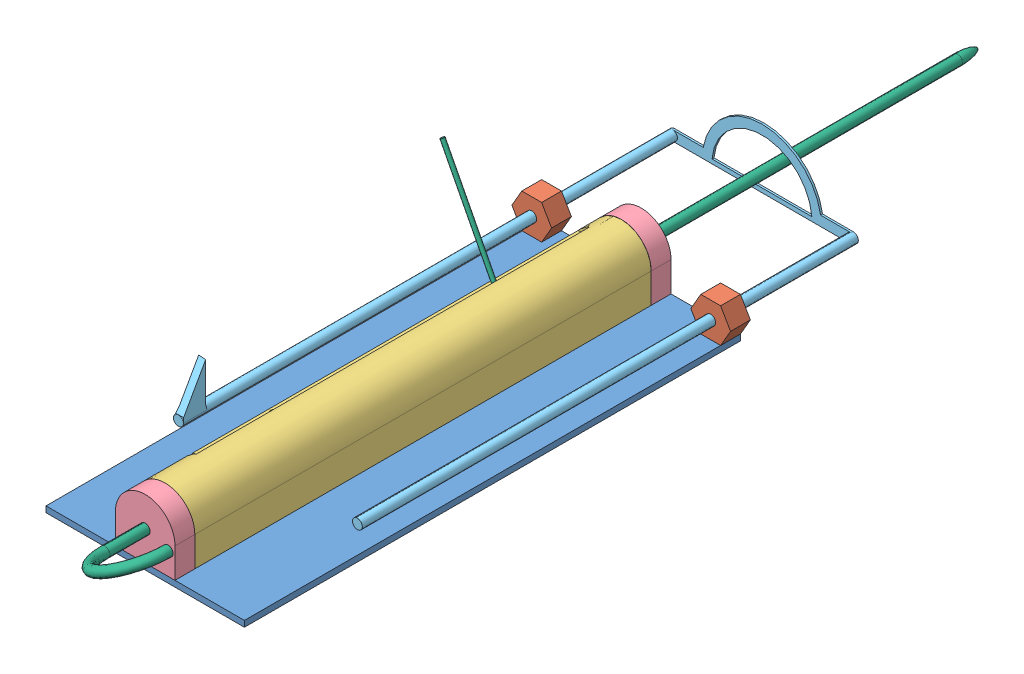
SolidWorks assembly first, configuration Default. Lengths in mm.
Overall size (110.2 109.57 460.1).
10 component instances, 7 part files, 15 mates.
Components (placement in the parent):
- βάση-1: βάση [Default] at (31.2253 106.149 101.923) x (0 0 1) z (-1 0 0) size (250 3 100)
- Βίδα-1: Βίδα [Default] at (31.0441 117.8093 91.4061) x (1 0 0) z (0 -1 0) size (20 10 17.32)
- Βίδα-2: Βίδα [Default] at (121.2441 117.8093 91.4061) x (1 0 0) z (0 -1 0) size (20 10 17.32)
- Σωλήνας-1: Σωλήνας [Default] at (76.5697 124.4973 -23.5939) x (1 0 0) z (0 -1 0) size (30 230 30) (hidden)
- Σωλήνας-2: Σωλήνας [Default] at (76.2441 124.149 331.4061) x (-1 0 0) z (0 -1 0) size (30 230 30)
- καπάκι-1: καπάκι [Default] at (76.2441 124.149 91.4061) x (1 0 0) z (0 -1 0) size (30 10 30)
- σκανδάλη2-1: σκανδάλη2 [Default<As Machined>] at (76.1441 115.3093 29.4831) x (1 0 0) z (0 -1 0) size (95.2 250.14 50)
- άξονας-1: άξονας [Default] at (76.2441 124.149 158.9193) x (0 0 -1) z (0.888042 0.459761 0) size (460.1 83.55 50.85)
- spring-1: spring [Default] at (76.7657 124.4776 163.5171) x (-0.464669 0.885233 -0.021076) z (0.88505 0.465055 0.020246) size (23.74 111.99 23.99)
- καπάκι-2: καπάκι [Default] at (76.2441 124.149 331.4061) x (1 0 0) z (0 -1 0) size (30 10 30)
Mates (geometry in assembly coordinates):
- Coincident2: coincident anti-aligned: line of βάση-1 through (126.2441 109.149 91.4061) axis (-1 0 0); line of Βίδα-2 through (116.2441 109.149 91.4061) axis (1 0 0)
- Coincident4: coincident: line of βάση-1 through (126.2441 109.149 341.4061) axis (0 0 -1); plane of Βίδα-2 through (126.2441 109.149 101.4061) normal (0.866025 -0.5 0)
- Coincident7: coincident aligned: plane of Σωλήνας-2 through (76.2441 109.149 101.4061) normal (0 -1 0); plane of καπάκι-1 through (76.2441 109.149 101.4061) normal (0 -1 0)
- Coincident10: coincident aligned: plane of Σωλήνας-2 through (61.2441 124.149 101.4061) normal (-1 0 0); plane of καπάκι-1 through (61.2441 124.149 101.4061) normal (-1 0 0)
- Coincident18: coincident anti-aligned: plane of Σωλήνας-2 through (76.2441 124.149 101.4061) normal (0 0 -1); plane of καπάκι-1 through (76.2441 124.149 101.4061) normal (0 0 1)
- ProfileCenter1: profile center anti-aligned: line of Σωλήνας-2 through (91.2441 109.149 331.4061) axis (-1 0 0); plane of βάση-1 through (31.2253 109.149 101.923) normal (0 1 0)
- Concentric2: concentric aligned: circle of Βίδα-2; cylinder of σκανδάλη2-1 through (121.2441 117.8093 279.4831) axis (0 0 -1) radius 2.5
- Concentric7: concentric aligned: circle of Βίδα-1; cylinder of σκανδάλη2-1 through (31.0441 117.8093 279.4831) axis (0 0 -1) radius 2.5
- Coincident26: coincident anti-aligned: line of βάση-1 through (126.2441 109.149 91.4061) axis (-1 0 0); line of Βίδα-1 through (26.0441 109.149 91.4061) axis (1 0 0)
- Lock1: lock: unknown of άξονας-1; unknown of spring-1
- Concentric8: concentric aligned: circle of καπάκι-1; cylinder of άξονας-1 through (76.2441 124.149 -68.0038) axis (0 0 1) radius 2.5
- Tangent2: tangent: line of Σωλήνας-2 through (70.2511 137.8998 111.6454) axis (0 0 1); cylinder of άξονας-1 through (76.2441 124.149 158.9193) axis (-0.459761 0.888042 0) radius 1
- Coincident27: coincident anti-aligned: plane of Σωλήνας-2 through (76.2441 124.149 331.4061) normal (0 0 1); plane of καπάκι-2 through (76.2441 124.149 331.4061) normal (0 0 -1)
- Concentric9: concentric aligned: circle of άξονας-1; circle of καπάκι-2
- Parallel1: parallel: plane of βάση-1 through (31.2253 109.149 101.923) normal (0 1 0); line of σκανδάλη2-1 through (31.0441 120.3093 29.4831) axis (1 0 0)
